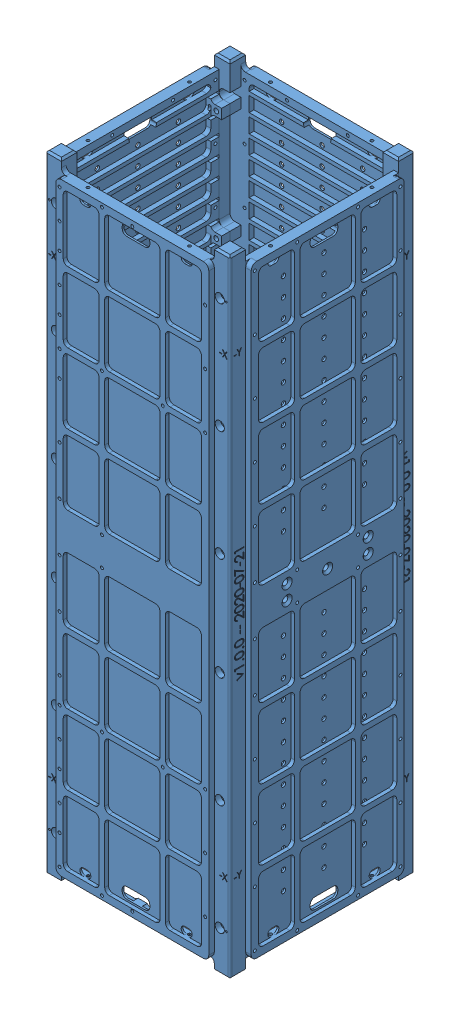
SolidWorks assembly 3UFrames, configuration Default. Lengths in mm.
Overall size (278.46 340 116.49).
4 component instances, 1 part files, 10 mates.
Components (placement in the parent):
- 3U_Frame-1: 3U_Frame [+X] at (-28.9892 9.8562 1.967) size (100 340 11.5)
- 3U_Frame-3: 3U_Frame [Y] at (-78.9892 9.9562 51.967) x (0 0 -1) z (1 0 0) size (99.75 327.5 11.5)
- 3U_Frame-4: 3U_Frame [Y] at (21.0108 9.9562 51.967) x (0 0 1) z (-1 0 0) size (99.75 327.5 11.5)
- 3U_Frame-5: 3U_Frame [-X] at (-28.9892 9.8562 101.967) x (-1 0 0) z (0 0 -1) size (278.46 340 11.5)
Mates (geometry in assembly coordinates):
- Coincident1: coincident anti-aligned: plane of 3U_Frame-1 through (-28.9892 9.8562 10.467) normal (0 0 1); plane of 3U_Frame-3 through (-76.3892 9.9562 10.467) normal (0 0 -1)
- Coincident2: coincident anti-aligned: plane of 3U_Frame-1 through (-28.9892 9.8562 10.467) normal (0 0 1); plane of 3U_Frame-4 through (18.4108 9.9562 10.467) normal (0 0 -1)
- Coincident6: coincident anti-aligned: plane of 3U_Frame-3 through (-76.3892 9.9562 93.467) normal (0 0 1); plane of 3U_Frame-5 through (-28.9892 9.8562 93.467) normal (0 0 -1)
- Coincident7: coincident aligned: plane of 3U_Frame-3 through (-70.4892 9.9562 51.967) normal (1 0 0); plane of 3U_Frame-5 through (-70.4892 160.5562 107.433) normal (1 0 0)
- Coincident9: coincident aligned: plane of 3U_Frame-4 through (12.5108 9.9562 51.967) normal (-1 0 0); plane of 3U_Frame-5 through (12.5108 160.5562 107.433) normal (-1 0 0)
- Coincident10: coincident aligned: plane of 3U_Frame-1 through (12.5108 9.8562 10.467) normal (-1 0 0); plane of 3U_Frame-4 through (12.5108 9.9562 51.967) normal (-1 0 0)
- Coincident11: coincident aligned: plane of 3U_Frame-1 through (-70.4892 9.8562 10.467) normal (1 0 0); plane of 3U_Frame-3 through (-70.4892 9.9562 51.967) normal (1 0 0)
- Coincident12: coincident aligned: line of 3U_Frame-1 through (12.5108 160.5562 4.567) axis (0 0 1); line of 3U_Frame-4 through (12.5108 160.5562 10.467) axis (0 0 1)
- Coincident13: coincident aligned: line of 3U_Frame-1 through (-70.4892 160.5562 4.567) axis (0 0 1); line of 3U_Frame-3 through (-70.4892 160.5562 10.467) axis (0 0 1)
- Coincident14: coincident aligned: line of 3U_Frame-3 through (-70.4892 160.5562 93.467) axis (0 0 -1); line of 3U_Frame-5 through (-70.4892 160.5562 97.1043) axis (0 0 -1)
